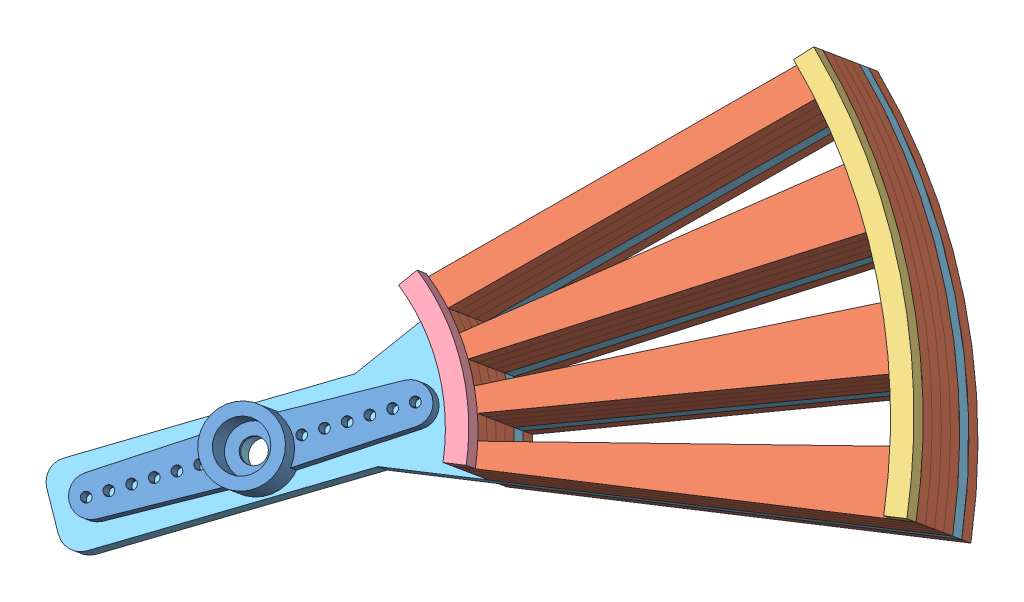
SolidWorks assembly Coin Assembly Coin Holder, configuration Default. Lengths in mm.
Overall size (86.45 52.05 68.59).
9 component instances, 5 part files, 25 mates.
Components (placement in the parent):
- Microservo horn-1: Microservo horn [По умолчанию] at (-5.665 -42.9874 8.9754) x (0.678115 0.347417 -0.647658) z (0.338464 0.634594 0.69479) size (32 7.5 5)
- Part1Middle-1: Part1Middle [Default] at (-1.6034 -35.3722 17.3129) x (-0.888605 -0.027346 0.457857) z (-0.338464 -0.634594 -0.69479) size (46.36 38.84 3)
- Part3Bottom-1: Part3Bottom [Default] at (-0.588 -33.4685 19.3973) x (-0.940974 0.230714 0.247667) z (-0.338464 -0.634594 -0.69479) size (27.41 30.99 3)
- Part4Bottom-1: Part4Bottom [Default] at (-1.6034 -35.3722 17.3129) x (0.262908 -0.772739 0.577715) z (0.338464 0.634594 0.69479) size (15.09 9.1 3)
- Part9Top-1: Part9Top [Default] at (-5.665 -42.9874 8.9754) x (-0.888605 -0.027346 0.457857) z (-0.338464 -0.634594 -0.69479) size (77.33 50.1 3)
- Part1Middle-2: Part1Middle [Default] at (-2.6188 -37.276 15.2285) x (-0.888605 -0.027346 0.457857) z (-0.338464 -0.634594 -0.69479) size (46.36 38.84 3)
- Part1Middle-3: Part1Middle [Default] at (-3.6342 -39.1798 13.1442) x (-0.888605 -0.027346 0.457857) z (-0.338464 -0.634594 -0.69479) size (46.36 38.84 3)
- Part1Middle-4: Part1Middle [Default] at (-4.6496 -41.0836 11.0598) x (-0.888605 -0.027346 0.457857) z (-0.338464 -0.634594 -0.69479) size (46.36 38.84 3)
- Part1Middle-5: Part1Middle [Default] at (-6.6804 -44.8912 6.891) x (-0.888605 -0.027346 0.457857) z (-0.338464 -0.634594 -0.69479) size (46.36 38.84 3)
Mates (geometry in assembly coordinates):
- Coincident1: coincident: plane of Part1Middle-1 through (-1.6034 -35.3722 17.3129) normal (0.338464 0.634594 0.69479); plane of Part3Bottom-1 through (-1.6034 -35.3722 17.3129) normal (-0.338464 -0.634594 -0.69479)
- Coincident2: coincident: circle of Part1Middle-1; circle of Part3Bottom-1
- Coincident3: coincident: point of Part1Middle-1; point of Part3Bottom-1
- Coincident4: coincident: plane of Part1Middle-1 through (-1.6034 -35.3722 17.3129) normal (0.338464 0.634594 0.69479); plane of Part4Bottom-1 through (-1.6034 -35.3722 17.3129) normal (-0.338464 -0.634594 -0.69479)
- Coincident5: coincident: circle of Part1Middle-1; circle of Part4Bottom-1
- Coincident6: coincident: point of Part1Middle-1; point of Part4Bottom-1
- Coincident7: coincident: plane of Part1Middle-1 through (-2.6188 -37.276 15.2285) normal (-0.338464 -0.634594 -0.69479); plane of Part1Middle-2 through (-2.6188 -37.276 15.2285) normal (0.338464 0.634594 0.69479)
- Coincident8: coincident: line of Part1Middle-1 through (14.9042 -36.1404 5.655) axis (0.876152 0.056784 -0.478678); line of Part1Middle-2 through (14.9042 -36.1404 5.655) axis (0.876152 0.056784 -0.478678)
- Coincident9: coincident: point of Part1Middle-1; point of Part1Middle-2
- Coincident10: coincident: plane of Part1Middle-2 through (-3.6342 -39.1798 13.1442) normal (-0.338464 -0.634594 -0.69479); plane of Part1Middle-3 through (-3.6342 -39.1798 13.1442) normal (0.338464 0.634594 0.69479)
- Coincident11: coincident: plane of Part1Middle-2 through (13.8889 -38.0441 3.5706) normal (0.343219 -0.770757 0.536781); plane of Part1Middle-3 through (12.8735 -39.9479 1.4862) normal (0.343219 -0.770757 0.536781)
- Coincident12: coincident: point of Part1Middle-2; point of Part1Middle-3
- Coincident13: coincident: plane of Part1Middle-3 through (-4.6496 -41.0836 11.0598) normal (-0.338464 -0.634594 -0.69479); plane of Part1Middle-4 through (-4.6496 -41.0836 11.0598) normal (0.338464 0.634594 0.69479)
- Coincident14: coincident: plane of Part1Middle-3 through (12.8735 -39.9479 1.4862) normal (0.343219 -0.770757 0.536781); plane of Part1Middle-4 through (11.8581 -41.8517 -0.5982) normal (0.343219 -0.770757 0.536781)
- Coincident15: coincident: point of Part1Middle-3; point of Part1Middle-4
- Coincident16: coincident: plane of Part9Top-1 through (-5.665 -42.9874 8.9754) normal (0.338464 0.634594 0.69479); plane of Part1Middle-4 through (-5.665 -42.9874 8.9754) normal (-0.338464 -0.634594 -0.69479)
- Coincident17: coincident: line of Part9Top-1 through (3.493 -42.3938 3.972) axis (0.876152 0.056784 -0.478678); line of Part1Middle-4 through (11.8581 -41.8517 -0.5982) axis (0.876152 0.056784 -0.478678)
- Coincident18: coincident: point of Part9Top-1; point of Part1Middle-4
- Coincident24: coincident: plane of Part9Top-1 through (-6.6804 -44.8912 6.891) normal (-0.338464 -0.634594 -0.69479); plane of Part1Middle-5 through (-6.6804 -44.8912 6.891) normal (0.338464 0.634594 0.69479)
- Coincident25: coincident: line of Part9Top-1 through (2.4776 -44.2976 1.8877) axis (0.876152 0.056784 -0.478678); line of Part1Middle-5 through (10.8427 -43.7555 -2.6825) axis (0.876152 0.056784 -0.478678)
- Coincident26: coincident: point of Part9Top-1; point of Part1Middle-5
- Concentric3: concentric: cylinder of Microservo horn-1 through (-5.665 -42.9874 8.9754) axis (0.338464 0.634594 0.69479) radius 2.5; cylinder of Part9Top-1 through (-6.6804 -44.8912 6.891) axis (0.338464 0.634594 0.69479) radius 1.5
- Concentric5: concentric: cylinder of Microservo horn-1 through (-5.665 -42.9874 8.9754) axis (0.338464 0.634594 0.69479) radius 2.5; cylinder of Part9Top-1 through (-6.6804 -44.8912 6.891) axis (0.338464 0.634594 0.69479) radius 1.5
- Distance3: distance = 4 mm: cylinder of Microservo horn-1 through (-1.9365 -40.1548 7.4505) axis (-0.338464 -0.634594 -0.69479) radius 0.5; line of Part9Top-1 through (-1.726 -36.871 1.4701) axis (-0.678115 -0.347417 0.647658)
- Coincident29: coincident: plane of Microservo horn-1 through (-5.665 -42.9874 8.9754) normal (-0.338464 -0.634594 -0.69479); plane of Part9Top-1 through (-5.665 -42.9874 8.9754) normal (0.338464 0.634594 0.69479)
